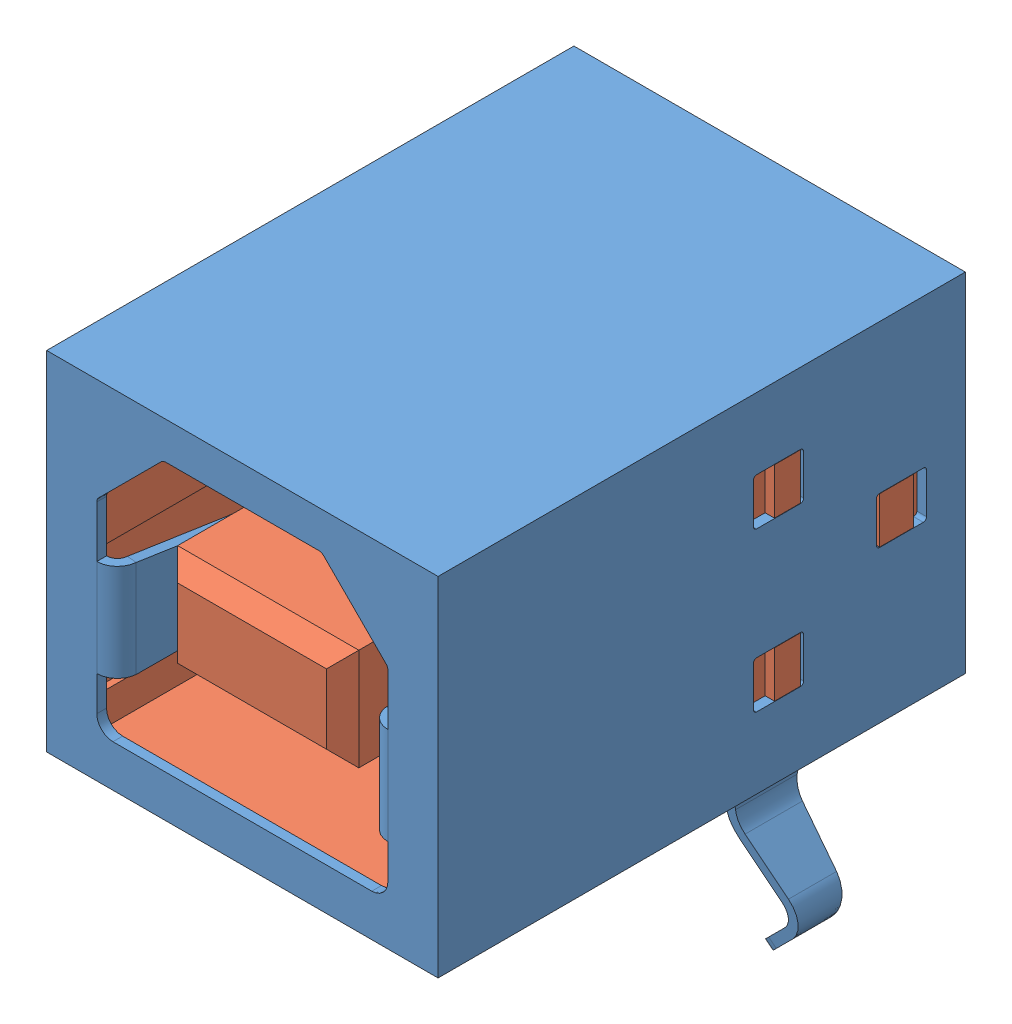
SolidWorks assembly USB-B, configuration Standard. Lengths in mm.
Overall size (14.85 14.97 16.3).
6 component instances, 3 part files, 0 mates.
Components (placement in the parent):
- USB-B-Housing-1: USB-B-Housing [Standard] x (-1 0 0) z (0 0 1) size (14.85 14.97 16.3)
- USB-B-Inner-1: USB-B-Inner [Standard] at (0 0 -15.7) x (-1 0 0) z (0 0 1) size (12.1 10.45 15.7)
- USB-B-Contacts-1: USB-B-Contacts [Standard] at (-0.575 1.075 -8.5) x (-1 0 0) z (0 1 0) size (1.35 12.17 0.84)
- USB-B-Contacts-2: USB-B-Contacts [Standard] at (1.925 1.075 -8.5) x (-1 0 0) z (0 1 0) size (1.35 12.17 0.84)
- USB-B-Contacts-3: USB-B-Contacts [Standard] at (-1.925 -1.475 -8.5) x (1 0 0) z (0 -1 0) size (1.35 12.17 0.84)
- USB-B-Contacts-4: USB-B-Contacts [Standard] at (0.575 -1.475 -8.5) x (1 0 0) z (0 -1 0) size (1.35 12.17 0.84)
